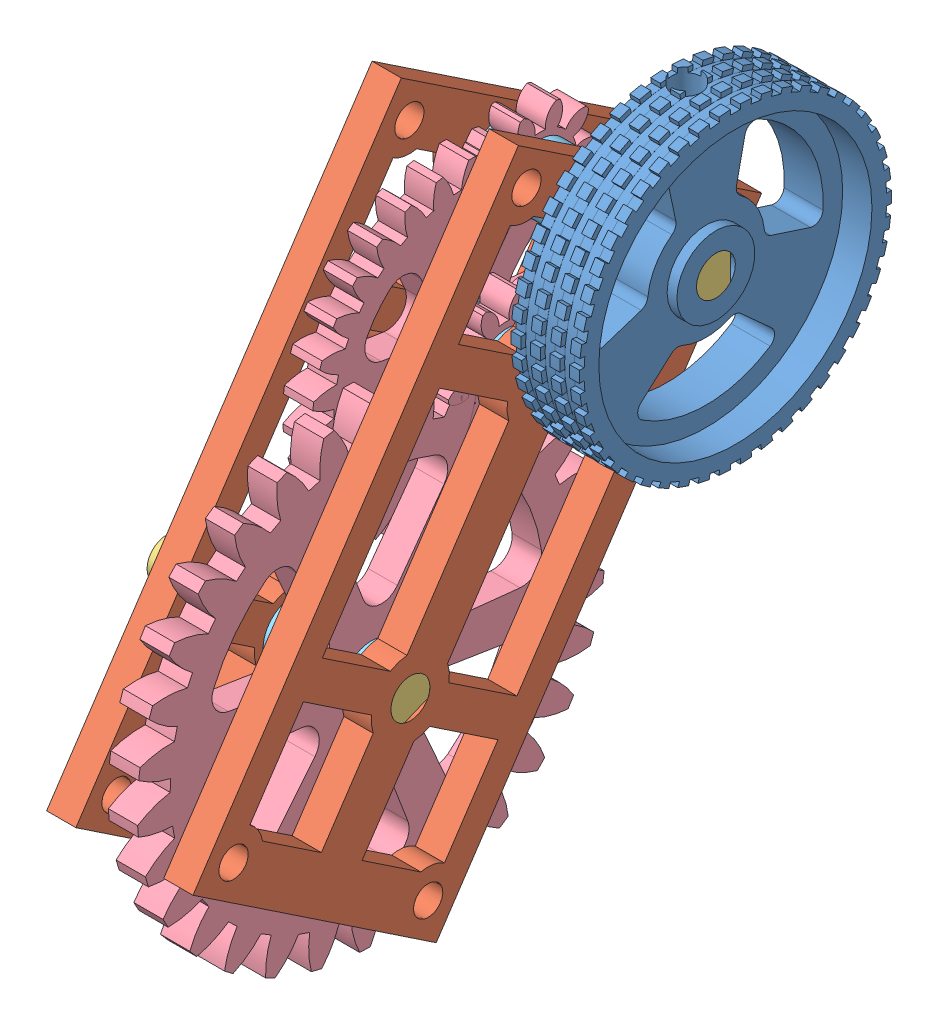
SolidWorks assembly Assem1, configuration Default. Lengths in mm.
Overall size (37 79.18 68.58).
20 component instances, 5 part files, 11 mates.
Components (placement in the parent):
- knob-1: knob [Default] at (12.5774 58.0909 -11.4082) size (7 31.99 32)
- plate-1: plate [Default] at (7.5774 36.4792 3.0464) x (0 -0.831219 0.555945) z (-1 0 0) size (60 30 3)
- Subassembly 1-1: Subassembly 1 [Default] at (15.5062 35.5628 -8.5164) x (0 0 1) z (-1 0 0) size (12 11.53 25)
  - axle-1: axle [25mm axle] at (-2.8918 22.5281 -2.0712) size (3.5 4 25)
  - root gear assignment-1: root gear assignment [10T 1.0Mod] at (-2.8918 22.5281 18.9288) x (-1 0 0) z (0 0 -1) size (12 11.53 3)
  - Spacer-1: Spacer [4.2-1] at (-2.8918 22.5281 18.9288) x (0.950881 0.309557 0) z (0 0 1) size (6.2 6.2 1)
  - Spacer-2: Spacer [4.2-5] at (-2.8918 22.5281 10.9288) x (-0.422504 -0.906361 0) z (0 0 1) size (6.2 6.2 5)
- Subassembly 2-1: Subassembly 2 [Default] at (-6.9192 49.4241 25.3315) x (0 -0.924225 -0.381849) z (1 0 0) size (32 31.89 15)
  - root gear assignment-1: root gear assignment [30T 1.0Mod] at (13.4314 26.1825 3.4966) size (32 31.89 3)
  - root gear assignment-2: root gear assignment [10T 1.0Mod] at (13.4314 26.1825 7.4966) size (12 11.53 3)
  - axle-1: axle [15mm axle] at (13.4314 26.1825 -0.5034) x (-1 0 0) z (0 0 1) size (3.5 4 15)
  - Spacer-1: Spacer [4.2-1] at (13.4314 26.1825 10.4966) size (6.2 6.2 1)
  - Spacer-3: Spacer [4.2-1] at (13.4314 26.1825 6.4966) size (6.2 6.2 1)
  - Spacer-4: Spacer [4.2-1] at (13.4314 26.1825 2.4966) size (6.2 6.2 1)
- Subassembly3-1: Subassembly3 [Default] at (-19.2923 29.7336 34.0662) x (0 -0.924225 -0.381849) z (1 0 0) size (48 47.84 25)
  - root gear assignment-1: root gear assignment [30T 1.5Mod] at (12.467 20.9936 19.8697) size (48 47.84 3)
  - axle-1: axle [25mm axle] at (12.467 20.9936 1.8697) x (-1 0 0) z (0 0 1) size (3.5 4 25)
  - Spacer-1: Spacer [4.2-1] at (12.467 20.9936 23.8697) x (-0.923728 -0.383049 0) z (0 0 -1) size (6.2 6.2 1)
  - Spacer-2: Spacer [4.2-5] at (12.467 20.9936 14.8697) size (6.2 6.2 5)
- plate-2: plate [Default] at (-4.4226 36.4792 3.0464) x (0 -0.831219 0.555945) z (-1 0 0) size (60 30 3)
Mates (geometry in assembly coordinates):
- Parallel1: parallel aligned: line of plate-1 through (7.5774 19.8818 32.193) axis (0 0.831219 -0.555945); line of plate-2 through (-7.4226 19.8818 32.193) axis (0 0.831219 -0.555945)
- Concentric3: concentric anti-aligned: cylinder of plate-1 through (7.5774 58.0909 -11.4082) axis (-1 0 0) radius 2; cylinder of Subassembly 1-1/axle-1 through (-7.4226 58.0909 -11.4082) axis (1 0 0) radius 2
- Concentric4: concentric anti-aligned: cylinder of Subassembly 1-1/axle-1 through (-7.4226 58.0909 -11.4082) axis (1 0 0) radius 2; cylinder of plate-2 through (-4.4226 58.0909 -11.4082) axis (-1 0 0) radius 2
- Coincident6: coincident aligned: plane of Subassembly 1-1/axle-1 through (-7.4226 58.0909 -11.4082) normal (-1 0 0); plane of plate-2 through (-7.4226 36.4792 3.0464) normal (-1 0 0)
- Concentric5: concentric anti-aligned: cylinder of knob-1 through (12.5774 58.0909 -11.4082) axis (-1 0 0) radius 2; cylinder of Subassembly 1-1/axle-1 through (-7.4226 58.0909 -11.4082) axis (1 0 0) radius 2
- Coincident7: coincident aligned: plane of knob-1 through (17.5774 62.0909 -11.4082) normal (1 0 0); plane of Subassembly 1-1/axle-1 through (17.5774 58.0909 -11.4082) normal (1 0 0)
- Coincident8: coincident anti-aligned: plane of plate-1 through (4.5774 36.4792 3.0464) normal (-1 0 0); plane of Subassembly 1-1/Spacer-2 through (4.5774 58.0909 -11.4082) normal (1 0 0)
- Concentric6: concentric aligned: cylinder of Subassembly 2-1/axle-1 through (7.5774 47.0082 -3.9958) axis (-1 0 0) radius 2; cylinder of plate-2 through (-4.4226 47.0082 -3.9958) axis (-1 0 0) radius 2
- Coincident9: coincident aligned: plane of plate-1 through (7.5774 36.4792 3.0464) normal (1 0 0); plane of Subassembly 2-1/axle-1 through (7.5774 47.0082 -3.9958) normal (1 0 0)
- Concentric7: concentric aligned: cylinder of plate-1 through (7.5774 26.2278 9.9029) axis (-1 0 0) radius 2; cylinder of Subassembly3-1/axle-1 through (7.5774 26.2278 9.9029) axis (-1 0 0) radius 2
- Coincident10: coincident aligned: plane of plate-1 through (7.5774 36.4792 3.0464) normal (1 0 0); plane of Subassembly3-1/axle-1 through (7.5774 26.2278 9.9029) normal (1 0 0)
